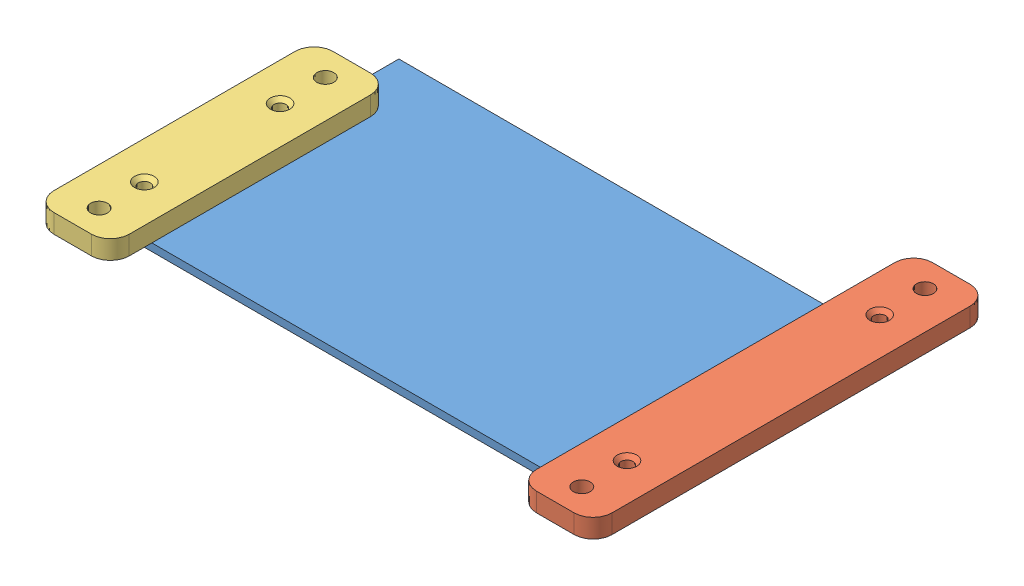
SolidWorks assembly Плата с крепежом, configuration По умолчанию. Lengths in mm.
Overall size (148 11 105).
3 component instances, 3 part files, 10 mates.
Components (placement in the parent):
- Плата ГМ-1: Плата ГМ [По умолчанию] x (1 0 0) z (0 0 -1) size (135 6 75)
- Пластина под плату широкая-2: Пластина под плату широкая [По умолчанию] at (121.5 9 90) x (0 0 -1) z (-1 0 0) size (105 5 20)
- Пластина под плату-4: Пластина под плату [По умолчанию] at (13.5 9 16) x (0 0 1) z (1 0 0) size (74 5 20)
Mates (geometry in assembly coordinates):
- Концентричный1: concentric aligned: cylinder of Плата ГМ-1 through (131.5 -2 71) axis (0 1 0) radius 1.5; cylinder of Пластина под плату широкая-2 through (131.5 4 71) axis (0 1 0) radius 1.6
- Совпадение1: coincident anti-aligned: plane of Плата ГМ-1 through (0 4 0) normal (0 1 0); plane of Пластина под плату широкая-2 through (121.5 4 90) normal (0 -1 0)
- Совпадение2: coincident anti-aligned: plane of Плата ГМ-1 through (0 0 0) normal (0 0 -1); plane of assembly through (0 0 0) normal (0 0 1)
- Совпадение3: coincident anti-aligned: plane of Плата ГМ-1 through (0 0 0) normal (0 -1 0); plane of assembly through (0 0 0) normal (0 1 0)
- Совпадение4: coincident aligned: plane of Плата ГМ-1; plane of assembly through (0 0 0) normal (1 0 0)
- Концентричный4: concentric aligned: cylinder of Плата ГМ-1 through (131.5 -2 4) axis (0 1 0) radius 1.5; cylinder of Пластина под плату широкая-2 through (131.5 4 4) axis (0 1 0) radius 1.6
- Концентричный5: concentric aligned: cylinder of Плата ГМ-1 through (3.5 -2 71) axis (0 1 0) radius 1.5; cylinder of Пластина под плату-4 through (3.5 4 71) axis (0 1 0) radius 1.6
- Концентричный6: concentric aligned: cylinder of Плата ГМ-1 through (3.5 -2 35) axis (0 1 0) radius 1.6; cylinder of Пластина под плату-4 through (3.5 4 35) axis (0 1 0) radius 1.6
- Совпадение5: coincident anti-aligned: plane of Плата ГМ-1 through (0 4 0) normal (0 1 0); plane of Пластина под плату-4 through (13.5 4 16) normal (0 -1 0)
- Совпадение6: coincident aligned: plane of Пластина под плату широкая-2 through (121.5 4 90) normal (0 0 1); plane of Пластина под плату-4 through (13.5 4 90) normal (0 0 1)
